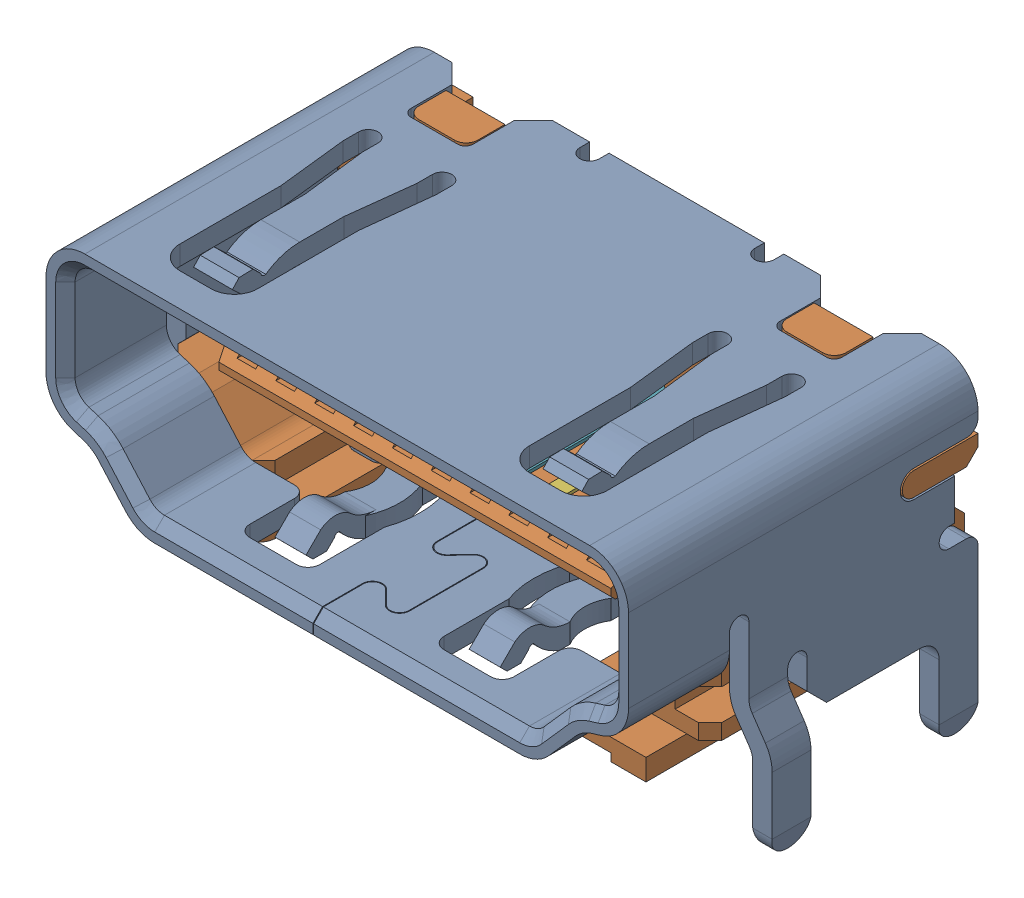
SolidWorks assembly raspberry_pi__HDMI_socket, configuration Default. Lengths in mm.
Overall size (16.2 8 9.9).
21 component instances, 4 part files, 0 mates.
Components (placement in the parent):
- raspberry_pi__HDMI_socket_cover-1: raspberry_pi__HDMI_socket_cover [Default] at (-20 0 0) size (16.2 8 9)
- raspberry_pi__HDMI_socket_inside-1: raspberry_pi__HDMI_socket_inside [Default] at (-20 0 0) size (15 6.1 7.6)
- raspberry_pi__HDMI_socket_large_pin-1: raspberry_pi__HDMI_socket_large_pin [Default] at (-201.7661 0.45 76.5103) x (0 0 -1) z (0 -1 0) size (7.55 0.65 3.84)
- raspberry_pi__HDMI_socket_small_pin-1: raspberry_pi__HDMI_socket_small_pin [Default] at (-202.2661 -0.25 76.5103) x (0 0 -1) z (0 -1 0) size (7.55 0.65 3.08)
- raspberry_pi__HDMI_socket_large_pin-2: raspberry_pi__HDMI_socket_large_pin [Default] at (-202.7661 0.45 76.5103) x (0 0 -1) z (0 -1 0) size (7.55 0.65 3.84)
- raspberry_pi__HDMI_socket_large_pin-3: raspberry_pi__HDMI_socket_large_pin [Default] at (-203.7661 0.45 76.5103) x (0 0 -1) z (0 -1 0) size (7.55 0.65 3.84)
- raspberry_pi__HDMI_socket_large_pin-4: raspberry_pi__HDMI_socket_large_pin [Default] at (-204.7661 0.45 76.5103) x (0 0 -1) z (0 -1 0) size (7.55 0.65 3.84)
- raspberry_pi__HDMI_socket_large_pin-5: raspberry_pi__HDMI_socket_large_pin [Default] at (-205.7661 0.45 76.5103) x (0 0 -1) z (0 -1 0) size (7.55 0.65 3.84)
- raspberry_pi__HDMI_socket_large_pin-6: raspberry_pi__HDMI_socket_large_pin [Default] at (-206.7661 0.45 76.5103) x (0 0 -1) z (0 -1 0) size (7.55 0.65 3.84)
- raspberry_pi__HDMI_socket_large_pin-7: raspberry_pi__HDMI_socket_large_pin [Default] at (-207.7661 0.45 76.5103) x (0 0 -1) z (0 -1 0) size (7.55 0.65 3.84)
- raspberry_pi__HDMI_socket_large_pin-8: raspberry_pi__HDMI_socket_large_pin [Default] at (-208.7661 0.45 76.5103) x (0 0 -1) z (0 -1 0) size (7.55 0.65 3.84)
- raspberry_pi__HDMI_socket_large_pin-9: raspberry_pi__HDMI_socket_large_pin [Default] at (-209.7661 0.45 76.5103) x (0 0 -1) z (0 -1 0) size (7.55 0.65 3.84)
- raspberry_pi__HDMI_socket_large_pin-10: raspberry_pi__HDMI_socket_large_pin [Default] at (-210.7661 0.45 76.5103) x (0 0 -1) z (0 -1 0) size (7.55 0.65 3.84)
- raspberry_pi__HDMI_socket_small_pin-2: raspberry_pi__HDMI_socket_small_pin [Default] at (-203.2661 -0.25 76.5103) x (0 0 -1) z (0 -1 0) size (7.55 0.65 3.08)
- raspberry_pi__HDMI_socket_small_pin-3: raspberry_pi__HDMI_socket_small_pin [Default] at (-204.2661 -0.25 76.5103) x (0 0 -1) z (0 -1 0) size (7.55 0.65 3.08)
- raspberry_pi__HDMI_socket_small_pin-4: raspberry_pi__HDMI_socket_small_pin [Default] at (-205.2661 -0.25 76.5103) x (0 0 -1) z (0 -1 0) size (7.55 0.65 3.08)
- raspberry_pi__HDMI_socket_small_pin-5: raspberry_pi__HDMI_socket_small_pin [Default] at (-206.2661 -0.25 76.5103) x (0 0 -1) z (0 -1 0) size (7.55 0.65 3.08)
- raspberry_pi__HDMI_socket_small_pin-6: raspberry_pi__HDMI_socket_small_pin [Default] at (-207.2661 -0.25 76.5103) x (0 0 -1) z (0 -1 0) size (7.55 0.65 3.08)
- raspberry_pi__HDMI_socket_small_pin-7: raspberry_pi__HDMI_socket_small_pin [Default] at (-208.2661 -0.25 76.5103) x (0 0 -1) z (0 -1 0) size (7.55 0.65 3.08)
- raspberry_pi__HDMI_socket_small_pin-8: raspberry_pi__HDMI_socket_small_pin [Default] at (-209.2661 -0.25 76.5103) x (0 0 -1) z (0 -1 0) size (7.55 0.65 3.08)
- raspberry_pi__HDMI_socket_small_pin-9: raspberry_pi__HDMI_socket_small_pin [Default] at (-210.2661 -0.25 76.5103) x (0 0 -1) z (0 -1 0) size (7.55 0.65 3.08)
